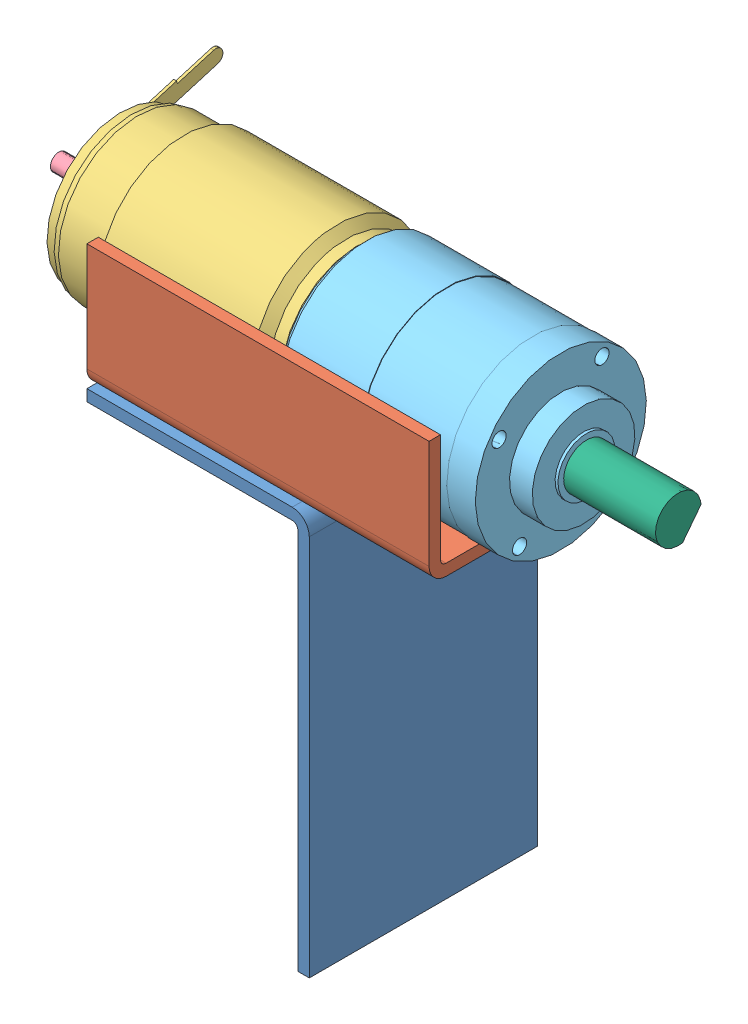
SolidWorks assembly Assemblage1, configuration Défaut. Lengths in mm.
Overall size (108.6 111.27 52.54).
7 component instances, 6 part files, 6 mates.
Components (placement in the parent):
- Pate moteur 1-1: Pate moteur 1 [Défaut] at (12.329 36.6391 -1.1576) size (39 70 40)
- Pate moteur2-1: Pate moteur2 [Défaut] at (-26.671 38.6391 36.8424) x (0 0 -1) z (1 0 0) size (12 22 60)
- Motoreducteur_Faulhauber_3042W024_30_1-1: Motoreducteur_Faulhauber_3042W024_30_1 [Default] at (-25.0181 51.2955 27.1793) x (0 -0.285334 0.958428) z (0 0.958428 0.285334) size (42.24 108.6 42.24)
  - corps_moteur_faulhauber_3042W024C-1: corps_moteur_faulhauber_3042W024C [Default] at (-5.2131 -12.6529 -1.1935) size (35.9 47.3 30)
  - arbre_moteur_faulhauber_3042W024C-1: arbre_moteur_faulhauber_3042W024C [Default] at (-5.2131 41.7471 -1.1935) x (0 -1 0) z (-0.776717 0 -0.629849) size (65.3 4 4)
  - corps_reducteur_faulhaber_30_1-1: corps_reducteur_faulhaber_30_1 [Default] at (-5.2131 64.4471 -1.1935) x (0.769654 0 -0.638462) z (0 -1 0) size (30 30 39.6)
  - arbre_reducteur_faulhauber_30_1-1: arbre_reducteur_faulhauber_30_1 [Default] at (-5.2131 64.4471 -1.1935) x (0.811588 0 -0.584231) z (0.584231 0 0.811588) size (8 20.6 8)
Mates (geometry in assembly coordinates):
- Coïncidente1: coincident anti-aligned: plane of Pate moteur 1-1 through (9.329 36.6391 38.8424) normal (0 1 0); plane of Pate moteur2-1 through (33.329 36.6391 35.8424) normal (0 -1 0)
- Coïncidente2: coincident aligned: plane of Pate moteur 1-1 through (9.329 33.6391 38.8424) normal (0 0 1); plane of Pate moteur2-1 through (33.329 58.6391 38.8424) normal (0 0 1)
- Coïncidente3: coincident aligned: plane of Pate moteur 1-1 through (-26.671 36.6391 38.8424) normal (-1 0 0); plane of Pate moteur2-1 through (-26.671 39.6391 35.8424) normal (-1 0 0)
- Tangent1: tangent anti-aligned: plane of Pate moteur 1-1 through (9.329 36.6391 38.8424) normal (0 1 0); cylinder of ?
- Tangent2: tangent anti-aligned: plane of Pate moteur2-1 through (33.329 58.6391 36.8424) normal (0 0 -1); cylinder of ?
- Coïncidente4: coincident aligned: plane of Pate moteur 1-1 through (-26.671 36.6391 38.8424) normal (-1 0 0); plane of ? through (-138.9778 51.6391 21.8424) normal (-1 0 0)
